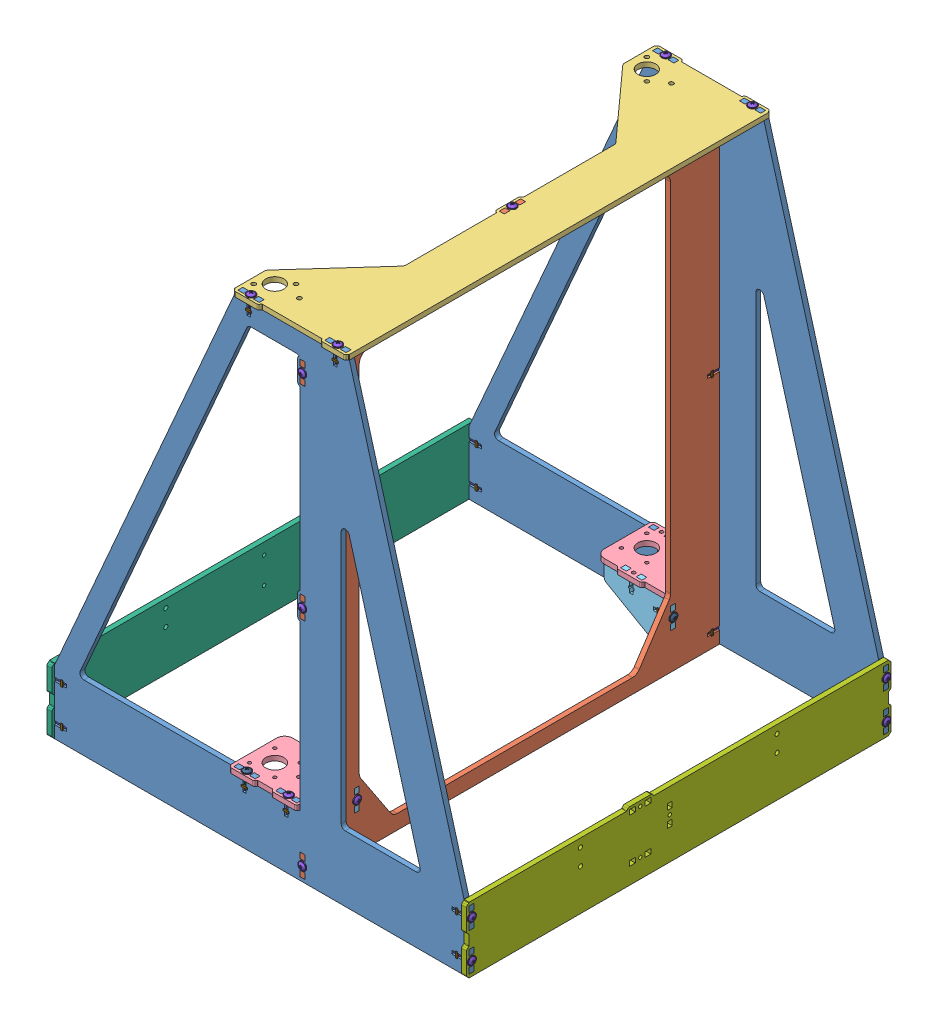
SolidWorks assembly frame, configuration По умолчанию. Lengths in mm.
Overall size (517.92 588.96 539.12).
58 component instances, 10 part files, 144 mates.
Components (placement in the parent):
- sidewall-2: sidewall [По умолчанию] at (426.2269 427.5104 420.8231) x (0 0 1) z (-1 0 0) size (6 586 512)
- cross-beam-1: cross-beam [По умолчанию] at (108.3378 743.5954 869.151) x (0 0 -1) z (-1 0 0) size (512 586 6)
- sidewall-3: sidewall [По умолчанию] at (426.2269 427.5104 926.8231) x (0 0 1) z (-1 0 0) size (6 586 512)
- frame_top-1: frame_top [По умолчанию] at (282.3378 763.1312 743.026) x (0 0 1) z (-1 0 0) size (518 6 140)
- bottom_bracket_h-2: bottom_bracket_h [По умолчанию] at (396.184 257.1312 932.8231) x (0 0 -1) z (0 -1 0) size (72 85 6)
- bottom_bracket_h-3: bottom_bracket_h [По умолчанию] at (396.184 263.1312 420.8231) x (0 0 1) z (0 1 0) size (72 85 6)
- bottom_bracket_v-1: bottom_bracket_v [По умолчанию] at (108.3378 550.9774 480.8231) x (-1 0 0) z (0 0 -1) size (81 66 6)
- bottom_bracket_v-2: bottom_bracket_v [По умолчанию] at (108.3378 550.9774 866.8231) x (-1 0 0) z (0 0 -1) size (81 66 6)
- front_bottom-1: front_bottom [По умолчанию] at (-197.6622 427.5104 420.8231) x (0 0 1) z (-1 0 0) size (518 79.92 6)
- rear_bottom-2: rear_bottom [По умолчанию] at (302.3378 18.6697 420.8231) x (0 0 1) z (1 0 0) size (518 83 6)
- DIN967-1: DIN967 [M4х20] at (39.3378 772.1812 929.8231) x (0 -1 0) z (0 0 1) size (22.96 34 34.42)
- din 562 m4-2: din 562 m4 [По умолчанию] at (39.3376 755.1312 929.8212) x (1 0 0) z (0 -1 0) size (7 7 2.2)
- DIN967-2: DIN967 [M4х20] at (145.3378 772.1812 929.8231) x (0 -1 0) z (0 0 1) size (22.96 34 34.42)
- din 562 m4-3: din 562 m4 [По умолчанию] at (145.3376 755.1312 929.8212) x (1 0 0) z (0 -1 0) size (7 7 2.2)
- DIN967-3: DIN967 [M4х20] at (39.3378 772.1812 423.8231) x (0 -1 0) z (0 0 -1) size (22.96 34 34.42)
- din 562 m4-4: din 562 m4 [По умолчанию] at (39.338 755.0489 423.8249) x (-1 0 0) z (0 -1 0) size (7 7 2.2)
- DIN967-4: DIN967 [M4х20] at (145.3378 772.1812 423.8231) x (0 -1 0) z (0 0 -1) size (22.96 34 34.42)
- din 562 m4-5: din 562 m4 [По умолчанию] at (145.338 755.0489 423.8249) x (-1 0 0) z (0 -1 0) size (7 7 2.2)
- DIN967-5: DIN967 [M4х20] at (-206.7122 246.0489 423.8231) x (1 0 0) z (0 0 -1) size (22.96 34 34.42)
- din 562 m4-6: din 562 m4 [По умолчанию] at (-189.6622 246.049 423.8249) x (0 -1 0) z (1 0 0) size (7 7 2.2)
- DIN967-6: DIN967 [M4х20] at (-206.7122 200.1312 423.8231) x (1 0 0) z (0 0 -1) size (22.96 34 34.42)
- din 562 m4-7: din 562 m4 [По умолчанию] at (-189.6622 200.1314 423.8249) x (0 -1 0) z (1 0 0) size (7 7 2.2)
- DIN967-7: DIN967 [M4х20] at (-206.7122 246.0489 929.8231) size (22.96 34 34.42)
- din 562 m4-8: din 562 m4 [По умолчанию] at (-189.6192 246.0487 929.8212) x (0 1 0) z (1 0 0) size (7 7 2.2)
- DIN967-8: DIN967 [M4х20] at (-206.7122 200.1312 929.8231) size (22.96 34 34.42)
- din 562 m4-9: din 562 m4 [По умолчанию] at (-189.6192 200.131 929.8212) x (0 1 0) z (1 0 0) size (7 7 2.2)
- DIN967-9: DIN967 [M4х20] at (311.3878 246.1312 929.8231) x (-1 0 0) z (0 0 1) size (22.96 34 34.42)
- din 562 m4-10: din 562 m4 [По умолчанию] at (294.3378 246.1314 929.8212) x (0 -1 0) z (-1 0 0) size (7 7 2.2)
- DIN967-10: DIN967 [M4х20] at (311.3878 200.1312 929.8231) x (-1 0 0) z (0 0 1) size (22.96 34 34.42)
- din 562 m4-11: din 562 m4 [По умолчанию] at (294.3378 200.1314 929.8212) x (0 -1 0) z (-1 0 0) size (7 7 2.2)
- DIN967-11: DIN967 [M4х20] at (311.3878 200.1312 423.8231) x (-1 0 0) z (0 0 -1) size (22.96 34 34.42)
- din 562 m4-13: din 562 m4 [По умолчанию] at (294.3808 200.131 423.8249) x (0 1 0) z (-1 0 0) size (7 7 2.2)
- DIN967-12: DIN967 [M4х20] at (311.3878 246.1312 423.8231) x (-1 0 0) z (0 0 -1) size (22.96 34 34.42)
- din 562 m4-12: din 562 m4 [По умолчанию] at (294.3808 246.131 423.8249) x (0 1 0) z (-1 0 0) size (7 7 2.2)
- DIN967-13: DIN967 [M4х20] at (105.3378 772.1812 676.8231) x (0 -1 0) z (-1 0 0) size (22.96 34 34.42)
- din 562 m4-14: din 562 m4 [По умолчанию] at (105.3397 755.1312 676.8229) x (0 0 1) z (0 -1 0) size (7 7 2.2)
- DIN967-14: DIN967 [M4х20] at (105.3378 200.1312 935.8731) x (0 0 -1) z (-1 0 0) size (22.96 34 34.42)
- din 562 m4-15: din 562 m4 [По умолчанию] at (105.3397 200.1314 918.8231) x (0 -1 0) z (0 0 -1) size (7 7 2.2)
- DIN967-15: DIN967 [M4х20] at (105.3378 473.1312 935.8731) x (0 0 -1) z (-1 0 0) size (22.96 34 34.42)
- din 562 m4-16: din 562 m4 [По умолчанию] at (105.3397 473.1314 918.8231) x (0 -1 0) z (0 0 -1) size (7 7 2.2)
- DIN967-16: DIN967 [M4х20] at (105.3378 473.1312 417.7731) x (0 0 1) z (-1 0 0) size (22.96 34 34.42)
- din 562 m4-17: din 562 m4 [По умолчанию] at (105.3397 473.131 434.8231) x (0 1 0) z (0 0 1) size (7 7 2.2)
- DIN967-17: DIN967 [M4х20] at (105.3378 721.1312 417.7731) x (0 0 1) z (-1 0 0) size (22.96 34 34.42)
- din 562 m4-18: din 562 m4 [По умолчанию] at (105.3397 721.131 434.8231) x (0 1 0) z (0 0 1) size (7 7 2.2)
- DIN967-18: DIN967 [M4х20] at (105.3378 200.1312 417.7731) x (0 0 1) z (-1 0 0) size (22.96 34 34.42)
- din 562 m4-19: din 562 m4 [По умолчанию] at (105.3397 200.131 434.8231) x (0 1 0) z (0 0 1) size (7 7 2.2)
- DIN967-19: DIN967 [M4х20] at (105.3378 721.1312 935.8731) x (0 0 -1) z (-1 0 0) size (22.96 34 34.42)
- din 562 m4-20: din 562 m4 [По умолчанию] at (105.3397 721.1314 918.8231) x (0 -1 0) z (0 0 -1) size (7 7 2.2)
- DIN967-20: DIN967 [M4х20] at (111.3878 240.1312 869.8231) x (-1 0 0) z (0 0 -1) size (22.96 34 34.42)
- din 562 m4-21: din 562 m4 [По умолчанию] at (94.3378 240.131 869.8249) x (0 1 0) z (-1 0 0) size (7 7 2.2)
- DIN967-21: DIN967 [M4х20] at (60.3378 266.1812 869.8231) x (0 -1 0) z (0 0 -1) size (22.96 34 34.42)
- din 562 m4-22: din 562 m4 [По умолчанию] at (60.338 249.1312 869.8249) x (-1 0 0) z (0 -1 0) size (7 7 2.2)
- DIN967-22: DIN967 [M4х20] at (85.3378 266.1812 929.8231) x (0 -1 0) z (0 0 1) size (22.96 34 34.42)
- din 562 m4-23: din 562 m4 [По умолчанию] at (85.3376 249.1312 929.8212) x (1 0 0) z (0 -1 0) size (7 7 2.2)
- DIN967_2-1: DIN967_2 [M4х20] at (111.3878 240.1312 483.8231) x (-1 0 0) z (0 0 1) size (22.96 34 34.42)
- din 562 m4-26: din 562 m4 [По умолчанию] at (94.3378 240.1314 483.8212) x (0 -1 0) z (-1 0 0) size (7 7 2.2)
- DIN967_2-2: DIN967_2 [M4х20] at (34.3378 266.1812 929.8231) x (0 -1 0) z (0 0 1) size (22.96 34 34.42)
- din 562 m4-28: din 562 m4 [По умолчанию] at (34.3376 249.1312 929.8212) x (1 0 0) z (0 -1 0) size (7 7 2.2)
Mates (geometry in assembly coordinates):
- Совпадение1: coincident aligned: plane of sidewall-2 through (22.3378 763.1312 426.8231) normal (0 1 0); plane of cross-beam-1 through (102.3378 763.1312 926.8231) normal (0 1 0)
- Совпадение2: coincident anti-aligned: plane of sidewall-2 through (297.3378 262.4444 426.8231) normal (0 0 1); plane of cross-beam-1 through (102.3378 183.1312 426.8231) normal (0 0 -1)
- Совпадение3: coincident aligned: plane of sidewall-2 through (102.3378 733.1312 426.8231) normal (-1 0 0); plane of cross-beam-1 through (102.3378 743.5954 869.151) normal (-1 0 0)
- Совпадение4: coincident aligned: plane of cross-beam-1 through (102.3378 743.5954 869.151) normal (-1 0 0); plane of sidewall-3 through (102.3378 733.1312 932.8231) normal (-1 0 0)
- Совпадение5: coincident aligned: plane of cross-beam-1 through (102.3378 763.1312 926.8231) normal (0 1 0); plane of sidewall-3 through (22.3378 763.1312 932.8231) normal (0 1 0)
- Совпадение6: coincident anti-aligned: plane of cross-beam-1 through (102.3378 183.1312 926.8231) normal (0 0 1); plane of sidewall-3 through (297.3378 262.4444 926.8231) normal (0 0 -1)
- Совпадение7: coincident anti-aligned: plane of cross-beam-1 through (102.3378 763.1312 926.8231) normal (0 1 0); plane of frame_top-1 through (28.3378 763.1312 896.8709) normal (0 -1 0)
- Совпадение8: coincident aligned: plane of sidewall-3 through (297.3378 262.4444 932.8231) normal (0 0 1); plane of frame_top-1 through (162.3378 769.1312 932.8231) normal (0 0 1)
- Совпадение9: coincident aligned: plane of cross-beam-1 through (102.3378 743.5954 869.151) normal (-1 0 0); plane of frame_top-1 through (102.3378 769.1312 803.6091) normal (-1 0 0)
- Совпадение20: coincident anti-aligned: plane of cross-beam-1 through (102.3378 743.5954 869.151) normal (-1 0 0); plane of bottom_bracket_v-1 through (102.3378 257.1312 486.8231) normal (1 0 0)
- Совпадение24: coincident anti-aligned: plane of cross-beam-1 through (102.3378 743.5954 869.151) normal (-1 0 0); plane of bottom_bracket_v-2 through (102.3378 257.1312 872.8231) normal (1 0 0)
- Совпадение25: coincident anti-aligned: plane of cross-beam-1 through (102.3378 743.5954 869.151) normal (-1 0 0); plane of bottom_bracket_h-2 through (102.3378 263.1312 932.8231) normal (1 0 0)
- Совпадение27: coincident aligned: plane of sidewall-3 through (17.3482 263.1312 932.8231) normal (0 1 0); plane of bottom_bracket_h-2 through (27.3378 263.1312 876.8231) normal (0 1 0)
- Совпадение28: coincident anti-aligned: plane of cross-beam-1 through (102.3378 743.5954 869.151) normal (-1 0 0); plane of bottom_bracket_h-3 through (102.3378 257.1312 420.8231) normal (1 0 0)
- Совпадение30: coincident aligned: plane of sidewall-2 through (17.3482 263.1312 426.8231) normal (0 1 0); plane of bottom_bracket_h-3 through (27.3378 263.1312 476.8231) normal (0 1 0)
- Совпадение31: coincident anti-aligned: plane of bottom_bracket_h-3 through (27.3378 257.1312 476.8231) normal (0 -1 0); plane of bottom_bracket_v-1 through (27.3378 257.1312 486.8231) normal (0 1 0)
- Совпадение32: coincident anti-aligned: plane of bottom_bracket_h-2 through (27.3378 257.1312 876.8231) normal (0 -1 0); plane of bottom_bracket_v-2 through (27.3378 257.1312 872.8231) normal (0 1 0)
- Совпадение33: coincident aligned: plane of bottom_bracket_h-2 through (102.3378 263.1312 866.8231) normal (0 0 -1); plane of bottom_bracket_v-2 through (32.3378 243.1312 866.8231) normal (0 0 -1)
- Совпадение34: coincident aligned: plane of bottom_bracket_h-3 through (102.3378 257.1312 486.8231) normal (0 0 1); plane of bottom_bracket_v-1 through (32.3378 243.1312 486.8231) normal (0 0 1)
- На месте1: in place: plane of sidewall-2 through (-167.6192 263.0489 426.8231) normal (-1 0 0); plane of ? through (-167.6192 0 0) normal (-1 0 0); moOrthogonalPlaneRef_w of sidewall-2 through (-167.6192 263.0489 426.8231) normal (-1 0 0); plane of ? through (-167.6192 0 0) normal (0 1 0); plane of sidewall-2 through (-167.6192 263.0489 426.8231) normal (-1 0 0); plane of ? through (-167.6192 0 0) normal (0 0 1); plane of sidewall-2 through (-197.6622 259.3506 426.8231) normal (-1 0 0); unknown of front_bottom-1
- Совпадение35: coincident aligned: plane of sidewall-2; plane of front_bottom-1
- Совпадение36: coincident aligned: moOrthogonalPlaneRef_w of sidewall-2 through (-197.6622 427.5104 420.8231) normal (0 1 0); plane of front_bottom-1 through (-197.6622 427.5104 420.8231) normal (0 1 0)
- Совпадение37: coincident anti-aligned: moOrthogonalPlaneRef_w of sidewall-2 through (-197.6622 427.5104 420.8231) normal (0 0 -1); plane of front_bottom-1 through (-197.6622 427.5104 420.8231) normal (0 0 1)
- Совпадение39: coincident aligned: plane of sidewall-2 through (297.3378 262.4444 420.8231) normal (0 0 -1); plane of rear_bottom-2 through (308.3378 263.1312 420.8231) normal (0 0 -1)
- Совпадение40: coincident aligned: plane of sidewall-2 through (-197.6622 183.1312 426.8231) normal (0 -1 0); plane of rear_bottom-2 through (308.3378 183.1312 420.8231) normal (0 -1 0)
- Совпадение41: coincident anti-aligned: plane of sidewall-2 through (302.3378 183.1312 426.8231) normal (1 0 0); plane of rear_bottom-2 through (302.3378 18.6697 420.8231) normal (-1 0 0)
- Совпадение42: coincident: line of sidewall-3 through (162.3378 763.1312 932.8231) axis (0 0 -1); plane of frame_top-1 through (162.3378 769.1312 420.8231) normal (1 0 0)
- Совпадение43: coincident: plane of sidewall-3 through (426.2269 427.5104 929.8231) normal (0 0 1); line of DIN967-1 through (39.3378 791.5545 929.8231) axis (0 -1 0)
- Совпадение44: coincident anti-aligned: plane of frame_top-1 through (28.3378 769.1312 896.8709) normal (0 1 0); plane of DIN967-1 through (41.3378 769.1312 929.8231) normal (0 -1 0)
- Совпадение45: coincident anti-aligned: plane of frame_top-1 through (162.3378 769.1312 932.8231) normal (0 0 1); plane of DIN967-1 through (39.3378 772.1812 932.8231) normal (0 0 -1)
- Концентричный4: concentric anti-aligned: cylinder of DIN967-1 through (39.3378 778.5312 929.8231) axis (0 1 0) radius 2; cylinder of din 562 m4-2 through (39.3378 755.1312 929.8231) axis (0 -1 0) radius 2
- Совпадение46: coincident anti-aligned: plane of din 562 m4-2 through (39.3376 755.1312 929.8212) normal (0 1 0); plane of sidewall-3 through (37.2378 755.1312 926.8231) normal (0 -1 0)
- Совпадение471: coincident anti-aligned: plane of frame_top-1 through (28.3378 769.1312 896.8709) normal (0 1 0); plane of DIN967-2 through (147.3378 769.1312 929.8231) normal (0 -1 0)
- Совпадение48: coincident anti-aligned: plane of frame_top-1 through (162.3378 769.1312 932.8231) normal (0 0 1); plane of DIN967-2 through (145.3378 772.1812 932.8231) normal (0 0 -1)
- Концентричный6: concentric anti-aligned: cylinder of DIN967-2 through (145.3378 778.5312 929.8231) axis (0 1 0) radius 2; cylinder of din 562 m4-3 through (145.3378 755.1312 929.8231) axis (0 -1 0) radius 2
- Совпадение49: coincident anti-aligned: plane of din 562 m4-3 through (145.3376 755.1312 929.8212) normal (0 1 0); plane of sidewall-3 through (143.2378 755.1312 926.8231) normal (0 -1 0)
- Совпадение50: coincident anti-aligned: plane of frame_top-1 through (22.3378 769.1312 896.8709) normal (-1 0 0); plane of DIN967-1 through (22.3378 772.1812 929.8231) normal (1 0 0)
- Совпадение51: coincident anti-aligned: plane of frame_top-1 through (162.3378 769.1312 420.8231) normal (1 0 0); plane of DIN967-2 through (162.3378 772.1812 929.8231) normal (-1 0 0)
- Совпадение52: coincident anti-aligned: plane of frame_top-1 through (22.3378 769.1312 420.8231) normal (0 0 -1); plane of DIN967-3 through (39.3378 772.1812 420.8231) normal (0 0 1)
- Совпадение53: coincident anti-aligned: plane of frame_top-1 through (28.3378 769.1312 896.8709) normal (0 1 0); plane of DIN967-3 through (37.3378 769.1312 423.8231) normal (0 -1 0)
- Совпадение54: coincident anti-aligned: plane of frame_top-1 through (22.3378 769.1312 456.7752) normal (-1 0 0); plane of DIN967-3 through (22.3378 772.1812 423.8231) normal (1 0 0)
- Концентричный8: concentric anti-aligned: cylinder of DIN967-3 through (39.3378 778.5312 423.8231) axis (0 1 0) radius 2; cylinder of din 562 m4-4 through (39.3378 755.0489 423.8231) axis (0 -1 0) radius 2
- Совпадение55: coincident anti-aligned: plane of frame_top-1 through (22.3378 769.1312 420.8231) normal (0 0 -1); plane of DIN967-4 through (145.3378 772.1812 420.8231) normal (0 0 1)
- Совпадение56: coincident anti-aligned: plane of frame_top-1 through (28.3378 769.1312 896.8709) normal (0 1 0); plane of DIN967-4 through (143.3378 769.1312 423.8231) normal (0 -1 0)
- Совпадение57: coincident anti-aligned: plane of frame_top-1 through (162.3378 769.1312 420.8231) normal (1 0 0); plane of DIN967-4 through (162.3378 772.1812 423.8231) normal (-1 0 0)
- Концентричный10: concentric anti-aligned: cylinder of DIN967-4 through (145.3378 778.5312 423.8231) axis (0 1 0) radius 2; cylinder of din 562 m4-5 through (145.3378 755.0489 423.8231) axis (0 -1 0) radius 2
- Совпадение581: coincident anti-aligned: plane of front_bottom-1 through (-203.6622 427.5104 420.8231) normal (-1 0 0); plane of DIN967-5 through (-203.6622 244.0489 423.8231) normal (1 0 0)
- Совпадение60: coincident: plane of sidewall-2 through (297.3378 262.4444 420.8231) normal (0 0 -1); line of DIN967-5 through (-204.6622 252.7698 420.8231) axis (0 -1 0)
- Совпадение61: coincident anti-aligned: plane of sidewall-2 through (297.3378 262.4444 420.8231) normal (0 0 -1); plane of DIN967-5 through (-206.7122 246.0489 420.8231) normal (0 0 1)
- Совпадение62: coincident anti-aligned: plane of front_bottom-1 through (-203.6622 263.0489 420.8231) normal (0 1 0); plane of DIN967-5 through (-206.7122 263.0489 423.8231) normal (0 -1 0)
- Концентричный12: concentric anti-aligned: cylinder of DIN967-5 through (-213.0622 246.0489 423.8231) axis (-1 0 0) radius 2; cylinder of din 562 m4-6 through (-189.6622 246.0489 423.8231) axis (1 0 0) radius 2
- Совпадение63: coincident anti-aligned: plane of din 562 m4-6 through (-189.6622 246.049 423.8249) normal (-1 0 0); plane of sidewall-2 through (-189.6622 248.1489 426.8231) normal (1 0 0)
- Совпадение641: coincident anti-aligned: plane of front_bottom-1 through (-203.6622 427.5104 420.8231) normal (-1 0 0); plane of DIN967-6 through (-203.6622 198.1312 423.8231) normal (1 0 0)
- Совпадение65: coincident anti-aligned: plane of front_bottom-1 through (-203.6622 183.1312 420.8231) normal (0 0 -1); plane of DIN967-6 through (-206.7122 200.1312 420.8231) normal (0 0 1)
- Совпадение66: coincident: line of front_bottom-1 through (-203.6622 183.1312 420.8231) axis (0 0 1); plane of DIN967-6 through (-206.7122 183.1312 423.8231) normal (0 1 0)
- Концентричный14: concentric anti-aligned: cylinder of DIN967-6 through (-213.0622 200.1312 423.8231) axis (-1 0 0) radius 2; cylinder of din 562 m4-7 through (-189.6622 200.1312 423.8231) axis (1 0 0) radius 2
- Совпадение67: coincident anti-aligned: plane of din 562 m4-7 through (-189.6622 200.1314 423.8249) normal (-1 0 0); plane of sidewall-2 through (-189.6622 202.2312 426.8231) normal (1 0 0)
- Совпадение681: coincident anti-aligned: plane of front_bottom-1 through (-203.6622 427.5104 420.8231) normal (-1 0 0); plane of DIN967-7 through (-203.6622 248.0489 929.8231) normal (1 0 0)
- Совпадение70: coincident anti-aligned: plane of sidewall-3 through (297.3378 262.4444 932.8231) normal (0 0 1); plane of DIN967-7 through (-206.7122 246.0489 932.8231) normal (0 0 -1)
- Совпадение71: coincident anti-aligned: plane of front_bottom-1 through (-203.6622 263.0489 420.8231) normal (0 1 0); plane of DIN967-7 through (-206.7122 263.0489 929.8231) normal (0 -1 0)
- Концентричный16: concentric anti-aligned: cylinder of DIN967-7 through (-213.0622 246.0489 929.8231) axis (-1 0 0) radius 2; cylinder of din 562 m4-8 through (-189.6192 246.0489 929.8231) axis (1 0 0) radius 2
- Совпадение721: coincident anti-aligned: plane of front_bottom-1 through (-203.6622 427.5104 420.8231) normal (-1 0 0); plane of DIN967-8 through (-203.6622 202.1312 929.8231) normal (1 0 0)
- Совпадение73: coincident anti-aligned: plane of sidewall-3 through (297.3378 262.4444 932.8231) normal (0 0 1); plane of DIN967-8 through (-206.7122 200.1312 932.8231) normal (0 0 -1)
- Совпадение74: coincident anti-aligned: plane of sidewall-3 through (-197.6622 183.1312 932.8231) normal (0 -1 0); plane of DIN967-8 through (-206.7122 183.1312 929.8231) normal (0 1 0)
- Концентричный18: concentric anti-aligned: cylinder of DIN967-8 through (-213.0622 200.1312 929.8231) axis (-1 0 0) radius 2; cylinder of din 562 m4-9 through (-189.6192 200.1312 929.8231) axis (1 0 0) radius 2
- Совпадение751: coincident anti-aligned: plane of rear_bottom-2 through (308.3378 18.6697 420.8231) normal (1 0 0); plane of DIN967-9 through (308.3378 244.1312 929.8231) normal (-1 0 0)
- Совпадение76: coincident anti-aligned: plane of rear_bottom-2 through (308.3378 263.1312 932.8231) normal (0 0 1); plane of DIN967-9 through (311.3878 246.1312 932.8231) normal (0 0 -1)
- Совпадение77: coincident anti-aligned: plane of rear_bottom-2 through (308.3378 263.1312 420.8231) normal (0 1 0); plane of DIN967-9 through (311.3878 263.1312 929.8231) normal (0 -1 0)
- Концентричный20: concentric anti-aligned: cylinder of DIN967-9 through (317.7378 246.1312 929.8231) axis (1 0 0) radius 2; cylinder of din 562 m4-10 through (294.3378 246.1312 929.8231) axis (-1 0 0) radius 2
- Совпадение78: coincident anti-aligned: plane of din 562 m4-10 through (294.3378 246.1314 929.8212) normal (1 0 0); plane of sidewall-3 through (294.3378 248.2312 926.8231) normal (-1 0 0)
- Совпадение79: coincident anti-aligned: plane of rear_bottom-2 through (308.3378 18.6697 420.8231) normal (1 0 0); plane of DIN967-10 through (308.3378 198.1312 929.8231) normal (-1 0 0)
- Совпадение80: coincident anti-aligned: plane of rear_bottom-2 through (308.3378 263.1312 932.8231) normal (0 0 1); plane of DIN967-10 through (311.3878 200.1312 932.8231) normal (0 0 -1)
- Совпадение81: coincident anti-aligned: plane of rear_bottom-2 through (308.3378 183.1312 420.8231) normal (0 -1 0); plane of DIN967-10 through (311.3878 183.1312 929.8231) normal (0 1 0)
- Концентричный22: concentric anti-aligned: cylinder of DIN967-10 through (317.7378 200.1312 929.8231) axis (1 0 0) radius 2; cylinder of din 562 m4-11 through (294.3378 200.1312 929.8231) axis (-1 0 0) radius 2
- Совпадение82: coincident anti-aligned: plane of din 562 m4-11 through (294.3378 200.1314 929.8212) normal (1 0 0); plane of sidewall-3 through (294.3378 202.2312 926.8231) normal (-1 0 0)
- Совпадение831: coincident anti-aligned: plane of rear_bottom-2 through (308.3378 18.6697 420.8231) normal (1 0 0); plane of DIN967-11 through (308.3378 202.1312 423.8231) normal (-1 0 0)
- Совпадение84: coincident anti-aligned: plane of rear_bottom-2 through (308.3378 18.6697 420.8231) normal (1 0 0); plane of DIN967-12 through (308.3378 248.1312 423.8231) normal (-1 0 0)
- Совпадение85: coincident anti-aligned: plane of DIN967-11 through (311.3878 200.1312 420.8231) normal (0 0 1); plane of sidewall-2 through (297.3378 262.4444 420.8231) normal (0 0 -1)
- Совпадение86: coincident anti-aligned: plane of sidewall-2 through (297.3378 262.4444 420.8231) normal (0 0 -1); plane of DIN967-12 through (311.3878 246.1312 420.8231) normal (0 0 1)
- Совпадение87: coincident anti-aligned: plane of sidewall-2 through (-197.6622 183.1312 426.8231) normal (0 -1 0); plane of DIN967-11 through (311.3878 183.1312 423.8231) normal (0 1 0)
- Совпадение88: coincident anti-aligned: plane of rear_bottom-2 through (308.3378 263.1312 420.8231) normal (0 1 0); plane of DIN967-12 through (311.3878 263.1312 423.8231) normal (0 -1 0)
- Концентричный24: concentric anti-aligned: cylinder of DIN967-12 through (317.7378 246.1312 423.8231) axis (1 0 0) radius 2; cylinder of din 562 m4-12 through (294.3808 246.1312 423.8231) axis (-1 0 0) radius 2
- Концентричный26: concentric anti-aligned: cylinder of DIN967-11 through (317.7378 200.1312 423.8231) axis (1 0 0) radius 2; cylinder of din 562 m4-13 through (294.3808 200.1312 423.8231) axis (-1 0 0) radius 2
- Совпадение891: coincident anti-aligned: plane of frame_top-1 through (28.3378 769.1312 896.8709) normal (0 1 0); plane of DIN967-13 through (105.3378 769.1312 678.8231) normal (0 -1 0)
- Совпадение90: coincident anti-aligned: plane of frame_top-1 through (102.3378 769.1312 803.6091) normal (-1 0 0); plane of DIN967-13 through (102.3378 772.1812 676.8231) normal (1 0 0)
- Совпадение91: coincident: point of DIN967-13
- Концентричный28: concentric anti-aligned: cylinder of DIN967-13 through (105.3378 778.5312 676.8231) axis (0 1 0) radius 2; cylinder of din 562 m4-14 through (105.3378 755.1312 676.8231) axis (0 -1 0) radius 2
- Совпадение92: coincident anti-aligned: plane of din 562 m4-14 through (105.3397 755.1312 676.8229) normal (0 1 0); plane of cross-beam-1 through (108.3378 755.1312 674.7231) normal (0 -1 0)
- Совпадение93: coincident anti-aligned: plane of sidewall-3 through (297.3378 262.4444 932.8231) normal (0 0 1); plane of DIN967-14 through (105.3378 198.1312 932.8231) normal (0 0 -1)
- Совпадение95: coincident anti-aligned: plane of cross-beam-1 through (102.3378 743.5954 869.151) normal (-1 0 0); plane of DIN967-14 through (102.3378 200.1312 935.8731) normal (1 0 0)
- Совпадение96: coincident anti-aligned: plane of sidewall-3 through (-197.6622 183.1312 932.8231) normal (0 -1 0); plane of DIN967-14 through (105.3378 183.1312 935.8731) normal (0 1 0)
- Концентричный31: concentric anti-aligned: cylinder of DIN967-14 through (105.3378 200.1312 942.2231) axis (0 0 1) radius 2; cylinder of din 562 m4-15 through (105.3378 200.1312 918.8231) axis (0 0 -1) radius 2
- Совпадение97: coincident anti-aligned: plane of din 562 m4-15 through (105.3397 200.1314 918.8231) normal (0 0 1); plane of cross-beam-1 through (108.3378 202.2312 918.8231) normal (0 0 -1)
- Совпадение981: coincident anti-aligned: plane of sidewall-3 through (297.3378 262.4444 932.8231) normal (0 0 1); plane of DIN967-15 through (105.3378 471.1312 932.8231) normal (0 0 -1)
- Совпадение99: coincident anti-aligned: plane of cross-beam-1 through (102.3378 743.5954 869.151) normal (-1 0 0); plane of DIN967-15 through (102.3378 473.1312 935.8731) normal (1 0 0)
- Совпадение100: coincident: unknown of DIN967-15
- Концентричный33: concentric anti-aligned: cylinder of DIN967-15 through (105.3378 473.1312 942.2231) axis (0 0 1) radius 2; cylinder of din 562 m4-16 through (105.3378 473.1312 918.8231) axis (0 0 -1) radius 2
- Совпадение101: coincident anti-aligned: plane of din 562 m4-16 through (105.3397 473.1314 918.8231) normal (0 0 1); plane of cross-beam-1 through (108.3378 475.2312 918.8231) normal (0 0 -1)
- Совпадение1021: coincident anti-aligned: plane of sidewall-2 through (297.3378 262.4444 420.8231) normal (0 0 -1); plane of DIN967-16 through (105.3378 475.1312 420.8231) normal (0 0 1)
- Совпадение103: coincident anti-aligned: plane of sidewall-2 through (102.3378 733.1312 426.8231) normal (-1 0 0); plane of DIN967-16 through (102.3378 473.1312 417.7731) normal (1 0 0)
- Совпадение104: coincident: unknown of DIN967-16
- Концентричный35: concentric anti-aligned: cylinder of DIN967-16 through (105.3378 473.1312 411.4231) axis (0 0 -1) radius 2; cylinder of din 562 m4-17 through (105.3378 473.1312 434.8231) axis (0 0 1) radius 2
- Совпадение105: coincident anti-aligned: plane of din 562 m4-17 through (105.3397 473.131 434.8231) normal (0 0 -1); plane of cross-beam-1 through (108.3378 471.0312 434.8231) normal (0 0 1)
- Совпадение1061: coincident anti-aligned: plane of sidewall-2 through (297.3378 262.4444 420.8231) normal (0 0 -1); plane of DIN967-17 through (105.3378 723.1312 420.8231) normal (0 0 1)
- Совпадение107: coincident anti-aligned: plane of cross-beam-1 through (102.3378 743.5954 869.151) normal (-1 0 0); plane of DIN967-17 through (102.3378 721.1312 417.7731) normal (1 0 0)
- Совпадение108: coincident: point of sidewall-2; plane of DIN967-17 through (105.3378 738.1312 417.7731) normal (0 -1 0)
- Концентричный37: concentric anti-aligned: cylinder of DIN967-17 through (105.3378 721.1312 411.4231) axis (0 0 -1) radius 2; cylinder of din 562 m4-18 through (105.3378 721.1312 434.8231) axis (0 0 1) radius 2
- Совпадение109: coincident anti-aligned: plane of din 562 m4-18 through (105.3397 721.131 434.8231) normal (0 0 -1); plane of cross-beam-1 through (108.3378 719.0312 434.8231) normal (0 0 1)
- Совпадение1101: coincident anti-aligned: plane of sidewall-2 through (297.3378 262.4444 420.8231) normal (0 0 -1); plane of DIN967-18 through (105.3378 202.1312 420.8231) normal (0 0 1)
- Совпадение111: coincident anti-aligned: plane of cross-beam-1 through (102.3378 743.5954 869.151) normal (-1 0 0); plane of DIN967-18 through (102.3378 200.1312 417.7731) normal (1 0 0)
- Совпадение112: coincident anti-aligned: plane of sidewall-2 through (-197.6622 183.1312 426.8231) normal (0 -1 0); plane of DIN967-18 through (105.3378 183.1312 417.7731) normal (0 1 0)
- Концентричный40: concentric anti-aligned: cylinder of DIN967-18 through (105.3378 200.1312 411.4231) axis (0 0 -1) radius 2; cylinder of din 562 m4-19 through (105.3378 200.1312 434.8231) axis (0 0 1) radius 2
- Совпадение113: coincident anti-aligned: plane of din 562 m4-19 through (105.3397 200.131 434.8231) normal (0 0 -1); plane of cross-beam-1 through (108.3378 198.0312 434.8231) normal (0 0 1)
- Совпадение1141: coincident anti-aligned: plane of sidewall-3 through (297.3378 262.4444 932.8231) normal (0 0 1); plane of DIN967-19 through (105.3378 719.1312 932.8231) normal (0 0 -1)
- Совпадение115: coincident anti-aligned: plane of sidewall-3 through (102.3378 733.1312 932.8231) normal (-1 0 0); plane of DIN967-19 through (102.3378 721.1312 935.8731) normal (1 0 0)
- Совпадение116: coincident: line of sidewall-3 through (97.3378 738.1312 932.8231) axis (-1 0 0); plane of DIN967-19 through (105.3378 738.1312 935.8731) normal (0 -1 0)
- Концентричный42: concentric anti-aligned: cylinder of DIN967-19 through (105.3378 721.1312 942.2231) axis (0 0 1) radius 2; cylinder of din 562 m4-20 through (105.3378 721.1312 918.8231) axis (0 0 -1) radius 2
- Совпадение117: coincident anti-aligned: plane of din 562 m4-20 through (105.3397 721.1314 918.8231) normal (0 0 1); plane of cross-beam-1 through (108.3378 723.2312 918.8231) normal (0 0 -1)
- Совпадение11421: coincident anti-aligned: plane of cross-beam-1 through (108.3378 743.5954 869.151) normal (1 0 0); plane of DIN967-20 through (108.3378 242.1312 869.8231) normal (-1 0 0)
- Совпадение1143: coincident anti-aligned: plane of bottom_bracket_v-2 through (32.3378 243.1312 866.8231) normal (0 0 -1); plane of DIN967-20 through (111.3878 240.1312 866.8231) normal (0 0 1)
- Совпадение1144: coincident: plane of DIN967-20 through (111.3878 257.1312 869.8231) normal (0 -1 0); line of bottom_bracket_h-2 through (102.3378 257.1312 866.8231) axis (-1 0 0)
- Концентричный45: concentric anti-aligned: cylinder of DIN967-20 through (117.7378 240.1312 869.8231) axis (1 0 0) radius 2; cylinder of din 562 m4-21 through (94.3378 240.1312 869.8231) axis (-1 0 0) radius 2
- Совпадение1145: coincident anti-aligned: plane of din 562 m4-21 through (94.3378 240.131 869.8249) normal (1 0 0); plane of bottom_bracket_v-2 through (94.3378 238.0312 872.8231) normal (-1 0 0)
- Совпадение1147: coincident anti-aligned: plane of bottom_bracket_h-2 through (27.3378 263.1312 876.8231) normal (0 1 0); plane of DIN967-21 through (58.3378 263.1312 869.8231) normal (0 -1 0)
- Совпадение1148: coincident anti-aligned: plane of bottom_bracket_h-2 through (102.3378 263.1312 866.8231) normal (0 0 -1); plane of DIN967-21 through (60.3378 266.1812 866.8231) normal (0 0 1)
- Концентричный47: concentric anti-aligned: cylinder of DIN967-21 through (60.3378 272.5312 869.8231) axis (0 1 0) radius 2; cylinder of din 562 m4-22 through (60.3378 249.1312 869.8231) axis (0 -1 0) radius 2
- Совпадение1150: coincident anti-aligned: plane of din 562 m4-22 through (60.338 249.1312 869.8249) normal (0 1 0); plane of bottom_bracket_v-2 through (62.4378 249.1312 872.8231) normal (0 -1 0)
- Совпадение1151: coincident anti-aligned: plane of bottom_bracket_h-2 through (27.3378 263.1312 876.8231) normal (0 1 0); plane of DIN967-22 through (87.3378 263.1312 929.8231) normal (0 -1 0)
- Концентричный49: concentric anti-aligned: cylinder of DIN967-22 through (85.3378 272.5312 929.8231) axis (0 1 0) radius 2; cylinder of din 562 m4-23 through (85.3378 249.1312 929.8231) axis (0 -1 0) radius 2
- Совпадение1154: coincident anti-aligned: plane of din 562 m4-23 through (85.3376 249.1312 929.8212) normal (0 1 0); plane of sidewall-3 through (83.2378 249.1312 926.8231) normal (0 -1 0)
- Совпадение11423: coincident anti-aligned: plane of sidewall-3 through (297.3378 262.4444 932.8231) normal (0 0 1); plane of DIN967-22 through (85.3378 266.1812 932.8231) normal (0 0 -1)
- Совпадение114321: coincident anti-aligned: plane of cross-beam-1 through (108.3378 743.5954 869.151) normal (1 0 0); plane of DIN967_2-1 through (108.3378 238.1312 483.8231) normal (-1 0 0)
- Совпадение11433: coincident anti-aligned: plane of bottom_bracket_v-1 through (32.3378 243.1312 486.8231) normal (0 0 1); plane of DIN967_2-1 through (111.3878 240.1312 486.8231) normal (0 0 -1)
- Совпадение11434: coincident anti-aligned: plane of bottom_bracket_v-1 through (27.3378 257.1312 486.8231) normal (0 1 0); plane of DIN967_2-1 through (111.3878 257.1312 483.8231) normal (0 -1 0)
- Концентричный58: concentric anti-aligned: cylinder of DIN967_2-1 through (117.7378 240.1312 483.8231) axis (1 0 0) radius 2; cylinder of din 562 m4-26 through (94.3378 240.1312 483.8231) axis (-1 0 0) radius 2
- Совпадение114322: coincident aligned: plane of cross-beam-1 through (102.3378 743.5954 869.151) normal (-1 0 0); plane of DIN967-22 through (102.3378 266.1812 929.8231) normal (-1 0 0)
- Расстояние2: distance = 25 mm aligned: plane of DIN967-21 through (77.3378 266.1812 869.8231) normal (-1 0 0); plane of cross-beam-1 through (102.3378 743.5954 869.151) normal (-1 0 0)
- Совпадение114329: coincident aligned: plane of sidewall-3 through (297.3378 262.4444 932.8231) normal (0 0 1); plane of bottom_bracket_h-2 through (17.3378 263.1312 932.8231) normal (0 0 1)
- Совпадение114330: coincident aligned: plane of sidewall-2 through (297.3378 262.4444 420.8231) normal (0 0 -1); plane of bottom_bracket_h-3 through (17.3378 257.1312 420.8231) normal (0 0 -1)
- Совпадение1143311: coincident anti-aligned: plane of bottom_bracket_h-2 through (27.3378 263.1312 876.8231) normal (0 1 0); plane of DIN967_2-2 through (36.3378 263.1312 929.8231) normal (0 -1 0)
- Совпадение114332: coincident anti-aligned: plane of bottom_bracket_h-2 through (17.3378 263.1312 932.8231) normal (0 0 1); plane of DIN967_2-2 through (34.3378 266.1812 932.8231) normal (0 0 -1)
- Совпадение114333: coincident anti-aligned: plane of bottom_bracket_h-2 through (17.3378 263.1312 876.8231) normal (-1 0 0); plane of DIN967_2-2 through (17.3378 266.1812 929.8231) normal (1 0 0)
- Концентричный63: concentric anti-aligned: cylinder of DIN967_2-2 through (34.3378 272.5312 929.8231) axis (0 1 0) radius 2; cylinder of din 562 m4-28 through (34.3378 249.1312 929.8231) axis (0 -1 0) radius 2
- Совпадение114334: coincident anti-aligned: plane of din 562 m4-28 through (34.3376 249.1312 929.8212) normal (0 1 0); plane of sidewall-3 through (32.2378 249.1312 926.8231) normal (0 -1 0)
